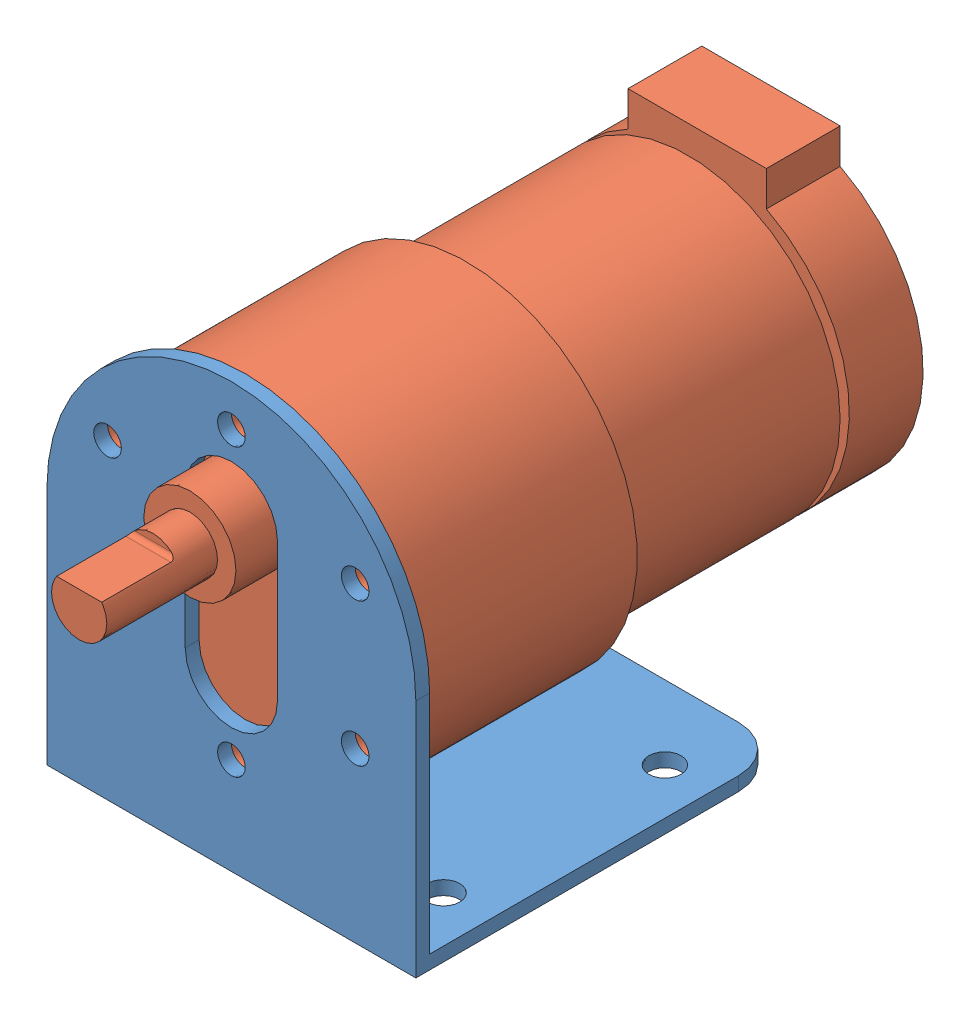
SolidWorks assembly 电机+支架, configuration 默认. Lengths in mm.
Overall size (40 46 75).
2 component instances, 2 part files, 3 mates.
Components (placement in the parent):
- 电机支架-1: 电机支架 [默认] at (3.3309 6.204 64.5) size (40 46 40)
- 减速比1：10【码盘减速电机】-1: 减速比1：10【码盘减速电机】 [默认] at (3.3309 6.204 40.5) size (37 37 75)
Mates (geometry in assembly coordinates):
- 同心1: concentric: cylinder of assembly; cylinder of assembly; cylinder of 电机支架-1 through (3.3309 6.204 66) axis (0 0 -1) radius 20; cylinder of 减速比1：10【码盘减速电机】-1 through (3.3309 6.204 64.5) axis (0 0 -1) radius 18.5
- 同心2: concentric: cylinder of assembly; cylinder of assembly; cylinder of 电机支架-1 through (3.3309 21.704 66) axis (0 0 -1) radius 1.5; cylinder of 减速比1：10【码盘减速电机】-1 through (3.3309 21.704 59.5) axis (0 0 1) radius 1.5
- 重合1: coincident: plane of assembly; plane of assembly; plane of 电机支架-1 through (3.3309 6.204 64.5) normal (0 0 -1); plane of 减速比1：10【码盘减速电机】-1 through (3.3309 6.204 64.5) normal (0 0 1)
